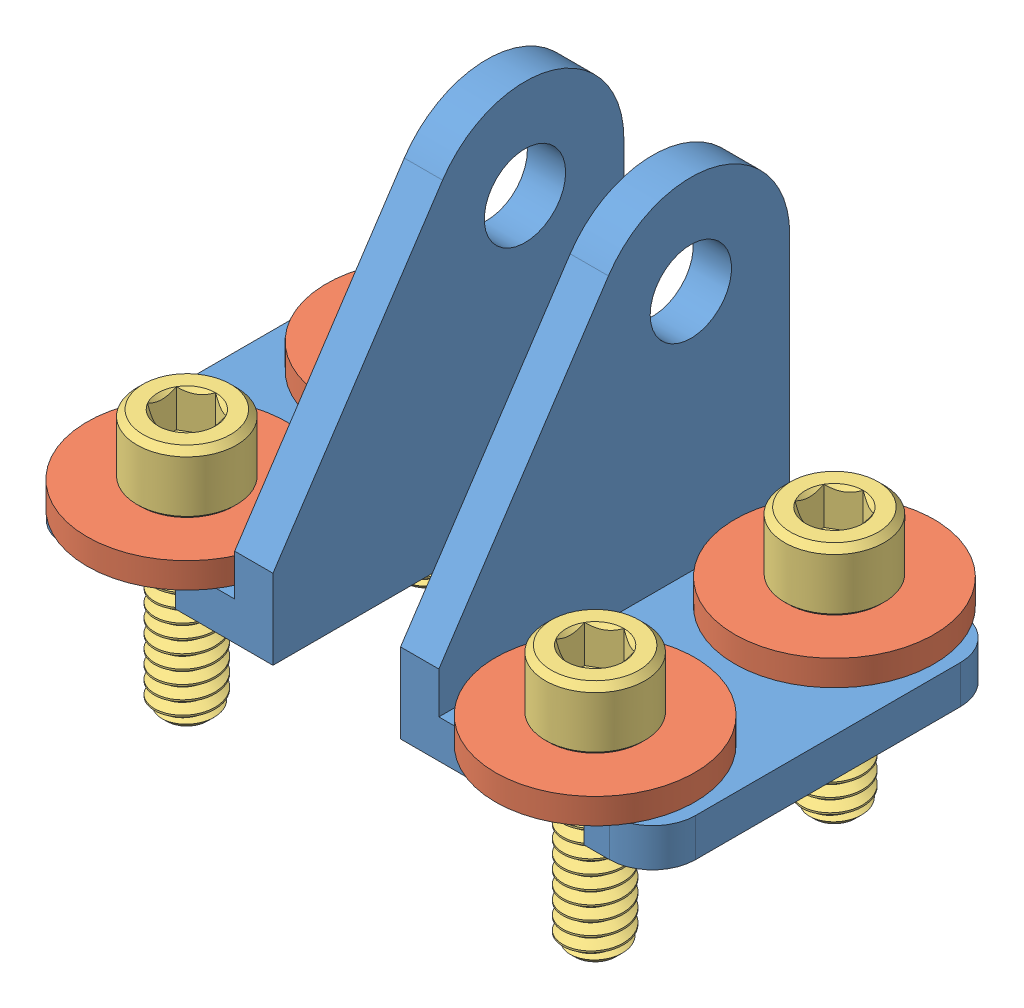
SolidWorks assembly Frame Side Bracket Assembly, configuration Default. Lengths in mm.
Overall size (50.29 41.41 34.93).
11 component instances, 3 part files, 16 mates.
Components (placement in the parent):
- Frame Side Brackets (NCM-PC075)-1: Frame Side Brackets (NCM-PC075) [NCM-PC075] at (-38.3587 -9.3003 16.2923) size (50.29 30.23 27.94)
  - NCM-PC075_NCMP-C-Bracket-1: NCM-PC075_NCMP-C-Bracket [075F] at (5.08 0 0) size (20.07 30.23 27.94)
  - NCM-PC075_NCMP-C-Bracket-2: NCM-PC075_NCMP-C-Bracket [075R] at (-5.08 0 0) x (-1 0 0) z (0 0 -1) size (20.07 30.23 27.94)
- SAE 0.25 Washer (MMC 91083A029)-1: SAE 0.25 Washer (MMC 91083A029) [91083A029] at (-54.6147 -4.2203 6.8943) x (0 -1 0) z (0 0 1) size (2.03 15.88 15.88)
- SAE 0.25 Washer (MMC 91083A029)-2: SAE 0.25 Washer (MMC 91083A029) [91083A029] at (-54.6147 -4.2203 25.9443) x (0 -1 0) z (0 0 1) size (2.03 15.88 15.88)
- SAE 0.25 Washer (MMC 91083A029)-3: SAE 0.25 Washer (MMC 91083A029) [91083A029] at (-22.1027 -4.2203 6.8943) x (0 -1 0) z (0 0 1) size (2.03 15.88 15.88)
- SAE 0.25 Washer (MMC 91083A029)-4: SAE 0.25 Washer (MMC 91083A029) [91083A029] at (-22.1027 -4.2203 25.9443) x (0 -1 0) z (0 0 1) size (2.03 15.88 15.88)
- Tab Bolt (MMC 91251A244)-1: Tab Bolt (MMC 91251A244) [91251A244] at (-22.1027 -20.0953 25.9443) x (1 0 0) z (0 -1 0) size (7.92 7.92 21.32)
- Tab Bolt (MMC 91251A244)-2: Tab Bolt (MMC 91251A244) [91251A244] at (-22.1027 -20.0953 6.8943) x (1 0 0) z (0 -1 0) size (7.92 7.92 21.32)
- Tab Bolt (MMC 91251A244)-3: Tab Bolt (MMC 91251A244) [91251A244] at (-54.6147 -20.0953 25.9443) x (1 0 0) z (0 -1 0) size (7.92 7.92 21.32)
- Tab Bolt (MMC 91251A244)-4: Tab Bolt (MMC 91251A244) [91251A244] at (-54.6147 -20.0953 6.8943) x (1 0 0) z (0 -1 0) size (7.92 7.92 21.32)
Mates (geometry in assembly coordinates):
- Concentric1: concentric: cylinder of Frame Side Brackets (NCM-PC075)-1/NCM-PC075_NCMP-C-Bracket-2 through (-54.6147 -6.2523 6.8943) axis (0 -1 0) radius 3.429; cylinder of SAE 0.25 Washer (MMC 91083A029)-1 through (-54.6147 -6.2523 6.8943) axis (0 1 0) radius 3.5687
- Concentric2: concentric: cylinder of Frame Side Brackets (NCM-PC075)-1/NCM-PC075_NCMP-C-Bracket-2 through (-54.6147 -6.2523 25.9443) axis (0 -1 0) radius 3.429; cylinder of SAE 0.25 Washer (MMC 91083A029)-2 through (-54.6147 -6.2523 25.9443) axis (0 1 0) radius 3.5687
- Concentric3: concentric: cylinder of Frame Side Brackets (NCM-PC075)-1/NCM-PC075_NCMP-C-Bracket-1 through (-22.1027 -6.2523 6.8943) axis (0 -1 0) radius 3.429; cylinder of SAE 0.25 Washer (MMC 91083A029)-3 through (-22.1027 -6.2523 6.8943) axis (0 1 0) radius 3.5687
- Concentric4: concentric: cylinder of Frame Side Brackets (NCM-PC075)-1/NCM-PC075_NCMP-C-Bracket-1 through (-22.1027 -6.2523 25.9443) axis (0 -1 0) radius 3.429; cylinder of SAE 0.25 Washer (MMC 91083A029)-4 through (-22.1027 -6.2523 25.9443) axis (0 1 0) radius 3.5687
- Coincident1: coincident anti-aligned: plane of Frame Side Brackets (NCM-PC075)-1/NCM-PC075_NCMP-C-Bracket-1 through (-22.1027 -6.2523 6.8943) normal (0 1 0); plane of SAE 0.25 Washer (MMC 91083A029)-3 through (-22.1027 -6.2523 6.8943) normal (0 -1 0)
- Coincident2: coincident anti-aligned: plane of Frame Side Brackets (NCM-PC075)-1/NCM-PC075_NCMP-C-Bracket-2 through (-54.6147 -6.2523 25.9443) normal (0 1 0); plane of SAE 0.25 Washer (MMC 91083A029)-1 through (-54.6147 -6.2523 6.8943) normal (0 -1 0)
- Coincident3: coincident anti-aligned: plane of Frame Side Brackets (NCM-PC075)-1/NCM-PC075_NCMP-C-Bracket-2 through (-54.6147 -6.2523 25.9443) normal (0 1 0); plane of SAE 0.25 Washer (MMC 91083A029)-2 through (-54.6147 -6.2523 25.9443) normal (0 -1 0)
- Coincident4: coincident anti-aligned: plane of Frame Side Brackets (NCM-PC075)-1/NCM-PC075_NCMP-C-Bracket-1 through (-22.1027 -6.2523 6.8943) normal (0 1 0); plane of SAE 0.25 Washer (MMC 91083A029)-4 through (-22.1027 -6.2523 25.9443) normal (0 -1 0)
- Concentric5: concentric: cylinder of SAE 0.25 Washer (MMC 91083A029)-1 through (-54.6147 -6.2523 6.8943) axis (0 1 0) radius 3.5687; cylinder of Tab Bolt (MMC 91251A244)-4 through (-54.6147 0.6057 6.8943) axis (0 -1 0) radius 3.9624
- Concentric6: concentric: cylinder of SAE 0.25 Washer (MMC 91083A029)-2 through (-54.6147 -6.2523 25.9443) axis (0 1 0) radius 3.5687; cylinder of Tab Bolt (MMC 91251A244)-3 through (-54.6147 0.6057 25.9443) axis (0 -1 0) radius 3.9624
- Concentric7: concentric: cylinder of SAE 0.25 Washer (MMC 91083A029)-4 through (-22.1027 -6.2523 25.9443) axis (0 1 0) radius 3.5687; cylinder of Tab Bolt (MMC 91251A244)-1 through (-22.1027 0.6057 25.9443) axis (0 -1 0) radius 3.9624
- Concentric8: concentric: cylinder of SAE 0.25 Washer (MMC 91083A029)-3 through (-22.1027 -6.2523 6.8943) axis (0 1 0) radius 3.5687; cylinder of Tab Bolt (MMC 91251A244)-2 through (-22.1027 0.6057 6.8943) axis (0 -1 0) radius 3.9624
- Coincident5: coincident anti-aligned: plane of SAE 0.25 Washer (MMC 91083A029)-2 through (-54.6147 -4.2203 25.9443) normal (0 1 0); plane of Tab Bolt (MMC 91251A244)-3 through (-54.6147 -4.2203 25.9443) normal (0 -1 0)
- Coincident6: coincident anti-aligned: plane of SAE 0.25 Washer (MMC 91083A029)-1 through (-54.6147 -4.2203 6.8943) normal (0 1 0); plane of Tab Bolt (MMC 91251A244)-4 through (-54.6147 -4.2203 6.8943) normal (0 -1 0)
- Coincident7: coincident anti-aligned: plane of SAE 0.25 Washer (MMC 91083A029)-4 through (-22.1027 -4.2203 25.9443) normal (0 1 0); plane of Tab Bolt (MMC 91251A244)-1 through (-22.1027 -4.2203 25.9443) normal (0 -1 0)
- Coincident8: coincident anti-aligned: plane of SAE 0.25 Washer (MMC 91083A029)-3 through (-22.1027 -4.2203 6.8943) normal (0 1 0); plane of Tab Bolt (MMC 91251A244)-2 through (-22.1027 -4.2203 6.8943) normal (0 -1 0)
